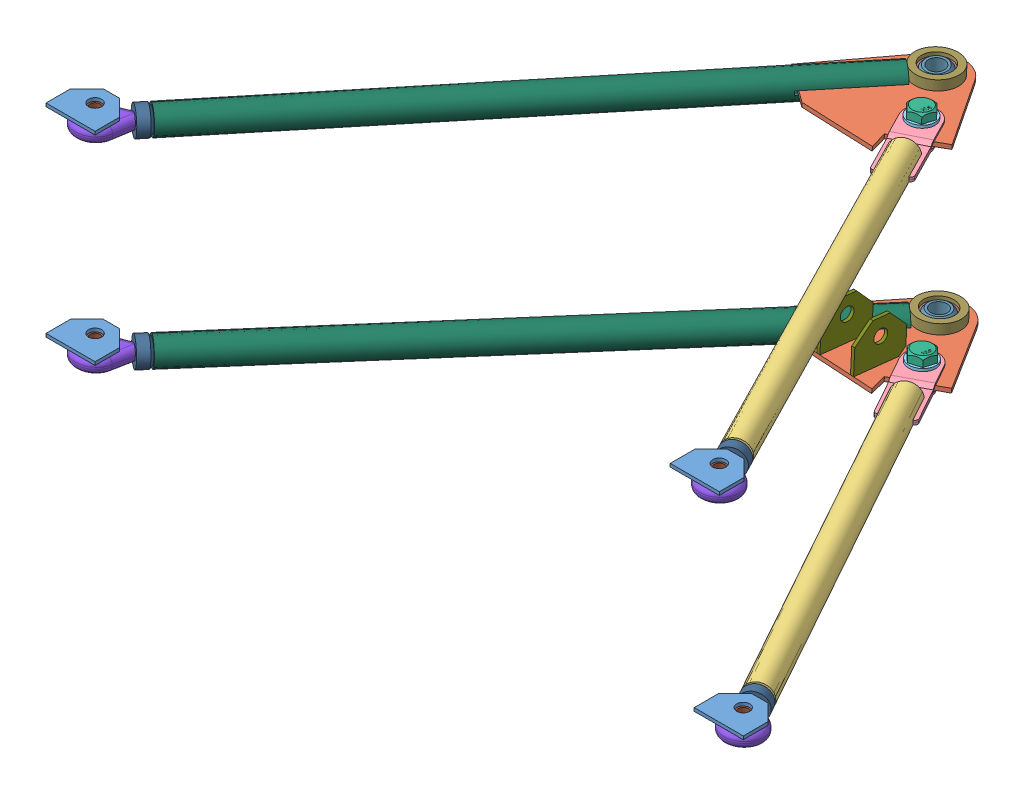
SolidWorks assembly Bell Crank and Control Arms V3, configuration Default. Lengths in mm.
Overall size (449.35 166.14 366.09).
52 component instances, 16 part files, 12 mates.
Components (placement in the parent):
- frame connectors-10: frame connectors [Default] at (-357.6393 7.7366 39.1204) size (30 2 25)
- frame connectors-11: frame connectors [Default] at (24.0053 7.7366 39.1204) size (30 2 25)
- Upper Control Arm Assembly-1: Upper Control Arm Assembly [Default] at (-132.0035 -138.9023 -250.945) x (0.997989 0.003304 0.063309) z (-0.063395 0.052016 0.996632) size (428.79 42.68 337.86) (flexible)
  - Front Control Arm Plate-1: Front Control Arm Plate [Default] at origin size (91 2.5 76.52)
  - Rear Upper Control Arm-2: Rear Upper Control Arm [Default] at (105.6055 0 154.4308) x (-0.554844 0 -0.831954) z (0.831954 0 -0.554844) size (250 16 16)
  - Control Arm Link Plate-1: Control Arm Link Plate [Default] at (31.8652 1.25 43.6848) x (-0.554844 0 -0.831954) z (0.831954 0 -0.554844) size (54.1 2.5 20)
  - Control Arm Link Plate-2: Control Arm Link Plate [Default] at (31.8652 -1.25 43.6848) x (-0.554844 0 -0.831954) z (-0.831954 0 0.554844) size (54.1 2.5 20)
  - plain washer normal grade a_iso-1: plain washer normal grade a_iso [Washer ISO 7089 - 8] at (22.4051 2.5 29.5) x (0 -1 0) z (0.774417 0 0.632675) size (1.6 16 16)
  - 94863A205_High-Strength Class 10.9 Steel Hex Head Screw-1: 94863A205_High-Strength Class 10.9 Steel Hex Head Screw [94863A205] at (22.4051 4.1 29.5) x (0.632675 0 -0.774417) z (0 1 0) size (13 16.35 25.89)
  - 94645A111_High-Strength Steel Nylon-Insert Locknut-1: 94645A111_High-Strength Steel Nylon-Insert Locknut [94645A111] at (22.4051 -6.5 29.5) x (-0.775473 0 -0.631381) z (-0.631381 0 0.775473) size (13 8 14.93)
  - Link Insert Assembly-1: Link Insert Assembly [Default] at (151.1806 41.9532 246.62) x (0.831954 0 -0.554844) z (0 -1 0) size (24 54 13.75) (flexible)
    - Link-1: Link [Default] at (13.2343 18.3157 41.9532) size (24 54 13.75)
    - Spherical Bearing Ball-1: Spherical Bearing Ball [Default] at (13.2343 47.8157 41.9532) x (0.026112 -0.045108 0.998641) z (0.47455 -0.878686 -0.052098) size (9 13.75 13.75)
  - Control Arm Insert-1: Control Arm Insert [Default] at (162.0573 0 239.0767) x (-0.831525 0.032128 0.554558) z (0.026729 0.999484 -0.017826) size (16 25 16)
  - 8mm Spehrical Bearing Insert-1: 8mm Spehrical Bearing Insert [Default] at (188.7427 6.4912 279.3957) x (-0.332123 0.050159 -0.941902) z (-0.94323 -0.014163 0.331837) size (11 9 11)
  - Spherical Bearing Seat-1: Spherical Bearing Seat [Default] at (0 -0.3 0) size (30 15.1 30)
  - Wide Spherical Bearing-1: Wide Spherical Bearing [Default] at (-7.3247 -16.3877 13.3464) x (1 0 0) z (0 1 0) size (26.76 26.96 14.68) (flexible)
    - Wide Bearing Cage-1: Wide Bearing Cage [Default] at (7.3247 13.3464 16.0877) size (22 22 10.5)
    - Wide Ball-1: Wide Ball [Default] at (7.3247 13.3464 16.0877) x (-0.803355 0.595088 0.022163) z (0.009626 -0.024235 0.99966) size (19.04 19.04 14)
  - Front Upper Control Arm-1: Front Upper Control Arm [Default] at (-100.6334 0 146.8287) x (0.559193 0 -0.829038) z (0.829038 0 0.559193) size (330 16 16)
  - Link Insert Assembly-2: Link Insert Assembly [Default] at (-191.0018 41.9532 257.1385) x (0.829038 0 0.559193) z (0 -1 0) size (24 54 13.75) (flexible)
    - Link-1: Link [Default] at (13.2343 18.3157 41.9532) size (24 54 13.75)
    - Spherical Bearing Ball-1: Spherical Bearing Ball [Default] at (13.2343 47.8157 41.9532) x (-0.031826 -0.041275 0.998641) z (-0.686072 -0.725683 -0.051858) size (9 13.75 13.75)
  - Control Arm Insert-2: Control Arm Insert [Default] at (-179.8953 0 264.3393) x (-0.82861 0.032128 -0.558904) z (0.026635 0.999484 0.017966) size (16 25 16)
  - 8mm Spehrical Bearing Insert-2: 8mm Spehrical Bearing Insert [Default] at (-206.7468 6.4912 304.5181) x (-0.995539 0.00819 -0.093998) z (-0.094297 -0.051473 0.994213) size (11 9 11)
  - Push Rod Upper Control Arm Bracket-1: Push Rod Upper Control Arm Bracket [Default] at (10.7762 13.75 44.5) x (0 0 1) z (0 -1 0) size (30 2 25)
  - Push Rod Upper Control Arm Bracket-2: Push Rod Upper Control Arm Bracket [Default] at (-11.2238 13.75 44.5) x (0 0 1) z (0 -1 0) size (30 2 25)
- frame connectors-14: frame connectors [Default] at (-357.6393 -114.2634 39.1204) size (30 2 25)
- frame connectors-15: frame connectors [Default] at (38.6473 -114.2634 39.1204) size (30 2 25)
- Lower Control Arm Assembly-4: Lower Control Arm Assembly [Default] at (-138.1243 -15.115 -255.6905) x (0.999096 0.001924 0.042477) z (-0.04252 0.045201 0.998073) size (414.39 25.89 337.86) (flexible)
  - Front Control Arm Plate-1: Front Control Arm Plate [Default] at origin size (91 2.5 76.52)
  - Rear Upper Control Arm-2: Rear Upper Control Arm [Default] at (98.5019 0 158.8804) x (-0.507538 0 -0.861629) z (0.861629 0 -0.507538) size (250 16 16)
  - Control Arm Link Plate-1: Control Arm Link Plate [Default] at (31.0586 1.25 44.1908) x (-0.507538 0 -0.861629) z (0.861629 0 -0.507538) size (54.1 2.5 20)
  - Control Arm Link Plate-2: Control Arm Link Plate [Default] at (31.0586 -1.25 44.1908) x (-0.507538 0 -0.861629) z (-0.861629 0 0.507538) size (54.1 2.5 20)
  - plain washer normal grade a_iso-1: plain washer normal grade a_iso [Washer ISO 7089 - 8] at (22.4051 2.5 29.5) x (0 -1 0) z (0.737893 0 0.674918) size (1.6 16 16)
  - 94863A205_High-Strength Class 10.9 Steel Hex Head Screw-1: 94863A205_High-Strength Class 10.9 Steel Hex Head Screw [94863A205] at (22.4051 4.1 29.5) x (0.674918 0 -0.737893) z (0 1 0) size (13 16.35 25.89)
  - 94645A111_High-Strength Steel Nylon-Insert Locknut-1: 94645A111_High-Strength Steel Nylon-Insert Locknut [94645A111] at (22.4051 -6.5 29.5) x (-0.772835 0 -0.634608) z (-0.634608 0 0.772835) size (13 8 14.93)
  - Link Insert Assembly-1: Link Insert Assembly [Default] at (138.8598 41.9532 253.4699) x (0.861629 0 -0.507538) z (0 -1 0) size (24 54 13.75) (flexible)
    - Link-1: Link [Default] at (13.2343 18.3157 41.9532) size (24 54 13.75)
    - Spherical Bearing Ball-1: Spherical Bearing Ball [Default] at (13.2343 47.8157 41.9532) x (0.021284 -0.039923 0.998976) z (-0.188545 0.981113 0.043226) size (9 13.75 13.75)
  - Control Arm Insert-1: Control Arm Insert [Default] at (150.1406 0 246.5455) x (-0.861184 0.032128 0.507276) z (0.027682 0.999484 -0.016306) size (16 25 16)
  - 8mm Spehrical Bearing Insert-1: 8mm Spehrical Bearing Insert [Default] at (174.5437 6.4933 288.2463) x (0.55455 -0.03868 0.831251) z (0.832148 0.023467 -0.554057) size (11 9 11)
  - Spherical Bearing Seat-1: Spherical Bearing Seat [Default] at (0 -0.3 0) size (30 15.1 30)
  - Wide Spherical Bearing-1: Wide Spherical Bearing [Default] at (-7.3247 -16.3877 13.3464) x (1 0 0) z (0 1 0) size (26.99 27.46 16.25) (flexible)
    - Wide Bearing Cage-1: Wide Bearing Cage [Default] at (7.3247 13.3464 16.0877) size (22 22 10.5)
    - Wide Ball-1: Wide Ball [Default] at (7.3247 13.3464 16.0877) x (-0.82616 0.558017 0.077951) z (0.040218 -0.079591 0.996016) size (19.04 19.04 14)
  - Front Upper Control Arm-1: Front Upper Control Arm [Default] at (-100.6334 0 146.8287) x (0.559193 0 -0.829038) z (0.829038 0 0.559193) size (330 16 16)
  - Link Insert Assembly-2: Link Insert Assembly [Default] at (-191.0018 41.9532 257.1385) x (0.829038 0 0.559193) z (0 -1 0) size (24 54 13.75) (flexible)
    - Link-1: Link [Default] at (13.2343 18.3157 41.9532) size (24 54 13.75)
    - Spherical Bearing Ball-1: Spherical Bearing Ball [Default] at (13.2343 47.8157 41.9532) x (-0.026871 -0.036398 0.998976) z (-0.732376 -0.679448 -0.044456) size (9 13.75 13.75)
  - Control Arm Insert-2: Control Arm Insert [Default] at (-179.8953 0 264.3393) x (-0.82861 0.032128 -0.558904) z (0.026635 0.999484 0.017966) size (16 25 16)
  - 8mm Spehrical Bearing Insert-2: 8mm Spehrical Bearing Insert [Default] at (-206.7557 6.4933 304.4738) x (-0.995506 0.006193 -0.094494) z (-0.094678 -0.044816 0.994499) size (11 9 11)
Mates (geometry in assembly coordinates):
- Concentric18: concentric aligned: cylinder of frame connectors-10 through (-357.6393 8.7366 39.1204) axis (0 -1 0) radius 4; cylinder of frame connectors-14 through (-357.6393 -113.2634 39.1204) axis (0 -1 0) radius 4
- Coincident27: coincident aligned: plane of frame connectors-10 through (-372.6393 8.7366 54.1204) normal (0 0 1); plane of frame connectors-14 through (-372.6393 -113.2634 54.1204) normal (0 0 1)
- Distance2: distance = 120 mm anti-aligned: plane of frame connectors-14 through (-357.6393 -113.2634 39.1204) normal (0 1 0); plane of frame connectors-10 through (-357.6393 6.7366 39.1204) normal (0 -1 0)
- Concentric19: concentric aligned: cylinder of Upper Control Arm Assembly-1/8mm Spehrical Bearing Insert-2 through (-357.6393 -117.2634 39.1204) axis (0 -1 0) radius 3; cylinder of frame connectors-14 through (-357.6393 -113.2634 39.1204) axis (0 -1 0) radius 4
- Coincident29: coincident anti-aligned: plane of Upper Control Arm Assembly-1/8mm Spehrical Bearing Insert-2 through (-352.2076 -115.2634 39.9847) normal (0 1 0); plane of frame connectors-14 through (-357.6393 -115.2634 39.1204) normal (0 -1 0)
- Coincident30: coincident aligned: plane of frame connectors-14 through (-372.6393 -113.2634 54.1204) normal (0 0 1); plane of frame connectors-15 through (23.6473 -113.2634 54.1204) normal (0 0 1)
- Coincident31: coincident aligned: plane of frame connectors-14 through (-357.6393 -113.2634 39.1204) normal (0 1 0); plane of frame connectors-15 through (38.6473 -113.2634 39.1204) normal (0 1 0)
- Concentric20: concentric aligned: cylinder of Upper Control Arm Assembly-1/8mm Spehrical Bearing Insert-1 through (38.6473 -117.2634 39.1204) axis (0 -1 0) radius 3; cylinder of frame connectors-15 through (38.6473 -113.2634 39.1204) axis (0 -1 0) radius 4
- Coincident32: coincident anti-aligned: plane of Upper Control Arm Assembly-1/8mm Spehrical Bearing Insert-1 through (40.1419 -115.2634 44.4135) normal (0 1 0); plane of frame connectors-15 through (38.6473 -115.2634 39.1204) normal (0 -1 0)
- Concentric21: concentric aligned: cylinder of frame connectors-10 through (-357.6393 8.7366 39.1204) axis (0 -1 0) radius 4; circle of Lower Control Arm Assembly-4/8mm Spehrical Bearing Insert-2
- Coincident33: coincident anti-aligned: plane of frame connectors-10 through (-357.6393 6.7366 39.1204) normal (0 -1 0); plane of Lower Control Arm Assembly-4/8mm Spehrical Bearing Insert-2 through (-352.191 6.7366 39.8732) normal (0 1 0)
- Concentric22: concentric aligned: cylinder of frame connectors-11 through (24.0053 8.7366 39.1204) axis (0 -1 0) radius 4; cylinder of Lower Control Arm Assembly-4/8mm Spehrical Bearing Insert-1 through (24.0053 4.7366 39.1204) axis (0 -1 0) radius 3
